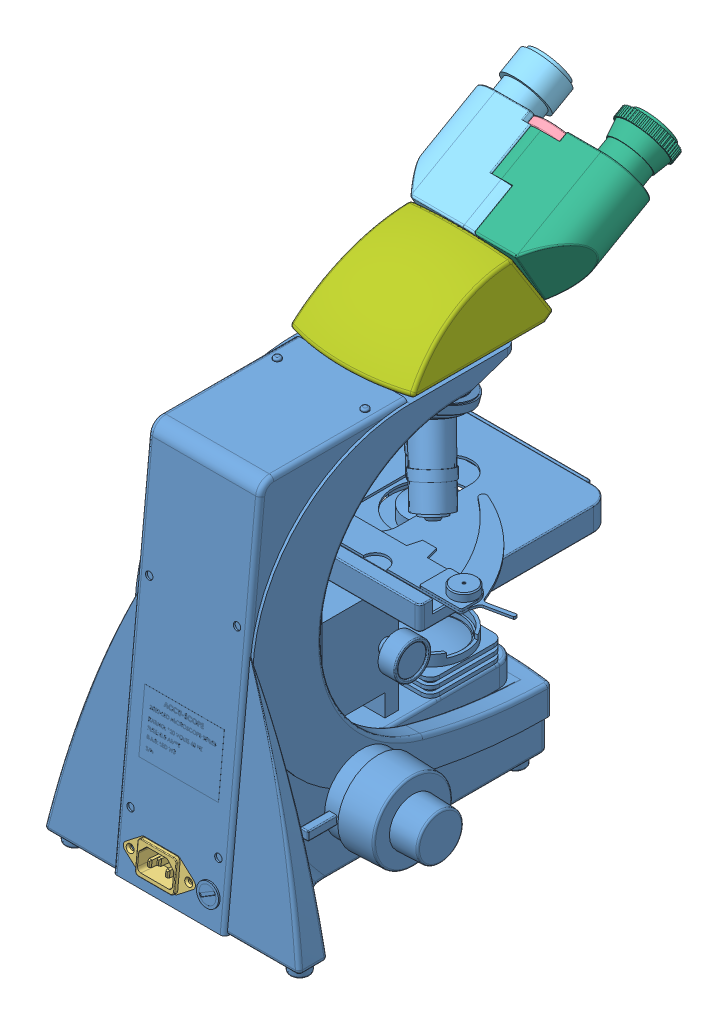
SolidWorks assembly User Library-3002 Series Microscope, configuration Default. Lengths in mm.
Overall size (252.97 408.49 388.59).
9 component instances, 8 part files, 13 mates.
Components (placement in the parent):
- User Library-3002 Series Microscope_Microscope-Base-1: User Library-3002 Series Microscope_Microscope-Base [Default] at origin size (252.97 269.32 319.18)
- User Library-3002 Series Microscope_Microscope Binocular-Cover-1: User Library-3002 Series Microscope_Microscope Binocular-Cover [Default] at (0 262.6995 -174.0839) size (67.06 9.02 67.06) (hidden)
- User Library-3002 Series Microscope_cap holding screw-1: User Library-3002 Series Microscope_cap holding screw [Default] at (-50.5232 255.016 -174.0839) x (0 0 1) z (-1 0 0) size (9 9 44.36)
- User Library-3002 Series Microscope_Recept_Power-Inlet_2-1: User Library-3002 Series Microscope_Recept_Power-Inlet_2 [Default] at (-8.255 13.2751 1.2314) x (-1 0 0) z (0 0.0971 0.995275) size (50.04 22.35 22.93)
- User Library-3002 Series Microscope_Binocular Viewing Head-1: User Library-3002 Series Microscope_Binocular Viewing Head [Default] at (0 318.318 -268.8309) x (1 0 0) z (0 -0.493606 0.869686) size (115.32 109.86 202.48)
  - User Library-3002 Series Microscope_EYEPIECE-ROT-1: User Library-3002 Series Microscope_EYEPIECE-ROT [Default] x (-1 0 0) z (0 0 -1) size (42.04 42.04 82.55)
  - User Library-3002 Series Microscope_EYEPIECE-L-1: User Library-3002 Series Microscope_EYEPIECE-L [Default] at (0 0 62.23) x (0 0 -1) z (0 -1 0) size (99.44 78.74 42.16)
  - User Library-3002 Series Microscope_EYEPIECE-R-1: User Library-3002 Series Microscope_EYEPIECE-R [Default] at (0 0 62.23) x (0 0 -1) z (0 1 0) size (99.44 78.74 42.16)
  - User Library-3002 Series Microscope_BINOCULAR-BASE-1: User Library-3002 Series Microscope_BINOCULAR-BASE [Default] at (0 -3.4511 108.7845) x (1 0 0) z (0 0.493606 0.869686) size (95.64 64.39 109.12)
Mates (geometry in assembly coordinates):
- Coincident1: coincident aligned: plane of User Library-3002 Series Microscope_Microscope-Base-1 through (0 0 0) normal (0 0 1); plane of assembly through (0 0 0) normal (0 0 1)
- Coincident2: coincident aligned: plane of User Library-3002 Series Microscope_Microscope-Base-1 through (0 0 0) normal (0 1 0); plane of assembly through (0 0 0) normal (0 1 0)
- Coincident3: coincident aligned: plane of User Library-3002 Series Microscope_Microscope-Base-1 through (0 0 0) normal (1 0 0); plane of assembly through (0 0 0) normal (1 0 0)
- Concentric1: concentric anti-aligned: cylinder of User Library-3002 Series Microscope_Microscope-Base-1 through (0 252.095 -174.0839) axis (0 1 0) radius 25.4; cylinder of User Library-3002 Series Microscope_Microscope Binocular-Cover-1 through (0 262.6995 -174.0839) axis (0 -1 0) radius 33.528
- Coincident4: coincident anti-aligned: plane of User Library-3002 Series Microscope_Microscope-Base-1 through (0 260.35 -174.0839) normal (0 1 0); plane of User Library-3002 Series Microscope_Microscope Binocular-Cover-1 through (33.528 260.35 -174.0839) normal (0 -1 0)
- Concentric2: concentric aligned: cylinder of User Library-3002 Series Microscope_Microscope-Base-1 through (-22.5298 255.016 -174.0839) axis (-1 0 0) radius 2.1; cylinder of User Library-3002 Series Microscope_cap holding screw-1 through (-20.5232 255.016 -174.0839) axis (-1 0 0) radius 2.5
- Tangent1: tangent anti-aligned: cylinder of User Library-3002 Series Microscope_Microscope Binocular-Cover-1 through (0 262.6995 -174.0839) axis (0 -1 0) radius 20.5232; plane of User Library-3002 Series Microscope_cap holding screw-1 through (-20.5232 255.016 -174.0839) normal (1 0 0)
- Distance3: distance = 8.255 mm anti-aligned: plane of User Library-3002 Series Microscope_Recept_Power-Inlet_2-1 through (-8.255 13.2751 1.2314) normal (-1 0 0); plane of assembly through (0 0 0) normal (1 0 0)
- Distance1: distance = 0.0254 mm aligned: plane of User Library-3002 Series Microscope_Microscope-Base-1 through (40.894 0 0) normal (0 0.0971 0.995275); plane of User Library-3002 Series Microscope_Recept_Power-Inlet_2-1 through (13.589 18.907 -1.8701) normal (0 0.0971 0.995275)
- Distance2: distance = 10.9728 mm aligned: plane of assembly through (0 0 0) normal (0 0.995275 -0.0971); plane of User Library-3002 Series Microscope_Recept_Power-Inlet_2-1 through (3.895 9.8086 -12.4667) normal (0 0.995275 -0.0971)
- Concentric3: concentric aligned: cylinder of User Library-3002 Series Microscope_Microscope-Base-1 through (0 252.095 -174.0839) axis (0 1 0) radius 25.4; cylinder of User Library-3002 Series Microscope_Binocular Viewing Head-1/User Library-3002 Series Microscope_BINOCULAR-BASE-1 through (0 254 -174.0839) axis (0 1 0) radius 18.415
- Coincident5: coincident anti-aligned: plane of User Library-3002 Series Microscope_Microscope-Base-1 through (0 260.35 -174.0839) normal (0 1 0); plane of User Library-3002 Series Microscope_Binocular Viewing Head-1/User Library-3002 Series Microscope_BINOCULAR-BASE-1 through (0 260.35 -174.0839) normal (0 -1 0)
- Coincident6: coincident aligned: plane of User Library-3002 Series Microscope_Binocular Viewing Head-1 through (0 318.318 -268.8309) normal (1 0 0); plane of assembly through (0 0 0) normal (1 0 0)
